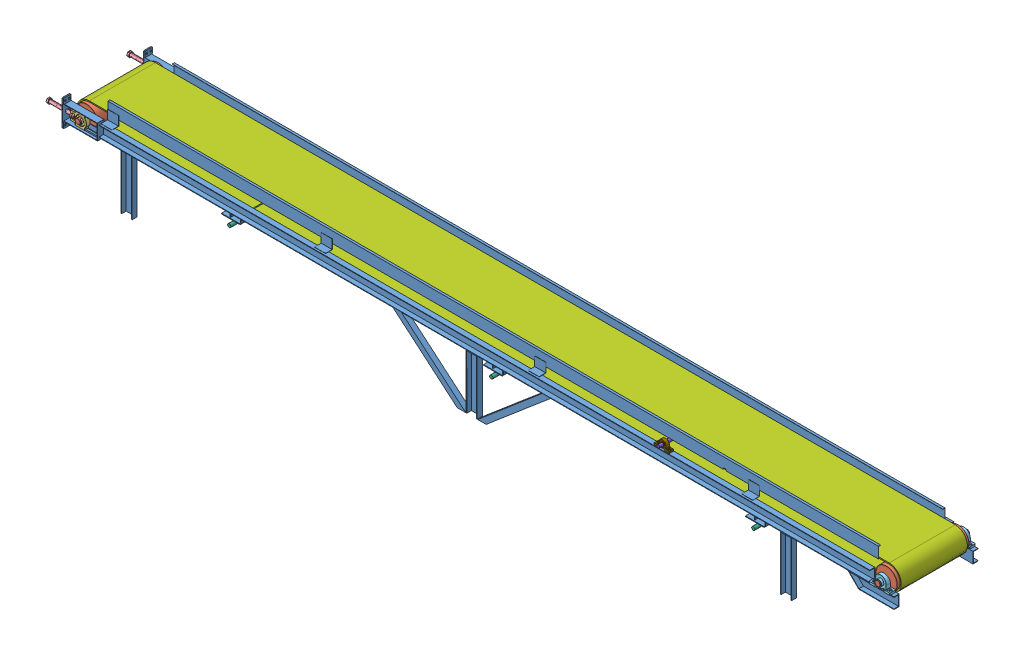
SolidWorks assembly Assieme4, configuration Default. Lengths in mm.
Overall size (7852.77 2195.2 815.72).
17 component instances, 9 part files, 1 mates.
Components (placement in the parent):
- nastrodx-1: nastrodx [Default] at (-736.9413 -3228.8791 379.4071) size (7852.77 2195.2 815.72)
  - C-channel -b-up-2: C-channel -b-up [Default<As Machined>] at (4036.4781 3775.6231 338.4141) x (0.000207 -1 -0.000382) z (-1 -0.000206 -0.000489) size (1248 810 7547.03)
  - roller-belt-Motor-up-1: roller-belt-Motor-up [Default] at (7631.6404 3780.4929 5.1727) x (0.000489 0.000382 -1) z (1 0 0.000489) size (812 200 200)
  - Uct 209-up-1: Uct 209-up [Default] at (366.4634 3774.8539 367.6204) x (1 0.000206 0.000489) z (-0.000489 -0.000382 1) size (144 117 54.7)
  - Extender-screw-up-1: Extender-screw-up [Default] at (302.9634 3774.8408 367.5894) x (0.000489 0 -1) z (-1 -0.000206 -0.000489) size (46.02 42.15 250)
  - Bearing-b_P209_45-up-1: Bearing-b_P209_45-up [Default] at (7631.4747 3726.3547 367.152) x (1 0.000206 0.000489) z (-0.000489 -0.000382 1) size (190 108 62)
  - upper-roller-inside-up-1: upper-roller-inside-up [Default] at (6502.8061 3649.373 4.571) x (1 0 0.000489) z (-0.000489 -0.000382 1) size (50 50 810)
  - Bearing-b_P209_45-up-2: Bearing-b_P209_45-up [Default] at (7631.8285 3726.6312 -356.8478) x (-1 -0.000206 -0.000489) z (0.000489 0.000382 -1) size (190 108 62)
  - Uct 209-up-2: Uct 209-up [Default] at (366.8211 3775.1334 -364.3794) x (1 0.000206 0.000489) z (0.000489 0.000382 -1) size (144 117 54.7)
  - Extender-screw-up-2: Extender-screw-up [Default] at (303.3211 3775.1203 -364.4105) x (0.000489 0.000764 -1) z (-1 -0.000206 -0.000489) size (46.02 42.15 250)
  - upper-roller-inside-up-2: upper-roller-inside-up [Default] at (4122.8064 3648.8818 3.4078) x (1 0 0.000489) z (-0.000489 -0.000382 1) size (50 50 810)
  - upper-roller-inside-up-3: upper-roller-inside-up [Default] at (1742.8067 3648.3906 2.2446) x (1 0 0.000489) z (-0.000489 -0.000382 1) size (50 50 810)
  - Belt-1: Belt [Default] at (4036.6418 3775.751 3.4142) x (-0.000207 1 0.000382) z (0.000489 0.000382 -1) size (228 7489 600)
  - roller-upper-2: roller-upper [Default] at (5639.6653 3862.5818 4.2307) x (1 0 0.000489) z (-0.000489 -0.000382 1) size (29 29 810)
  - UCP-205-1: UCP-205 [Default] at (5639.4923 3862.4467 358.2306) x (0.000489 0.000382 -1) z (1 0 0.000489) size (38.7 70 140)
  - UCP-205-2: UCP-205 [Default] at (5639.8383 3862.717 -349.7693) x (0.000489 0.000382 -1) z (1 0.000206 0.000489) size (38.7 70 140)
  - roller-belt-Motor-up-2: roller-belt-Motor-up [Default] at (366.6414 3778.9936 1.622) x (0.000489 0.000382 -1) z (1 0 0.000489) size (812 200 200)
Mates (geometry in assembly coordinates):
- Coincidente9: coincident: point of nastrodx-1/C-channel -b-up-2
